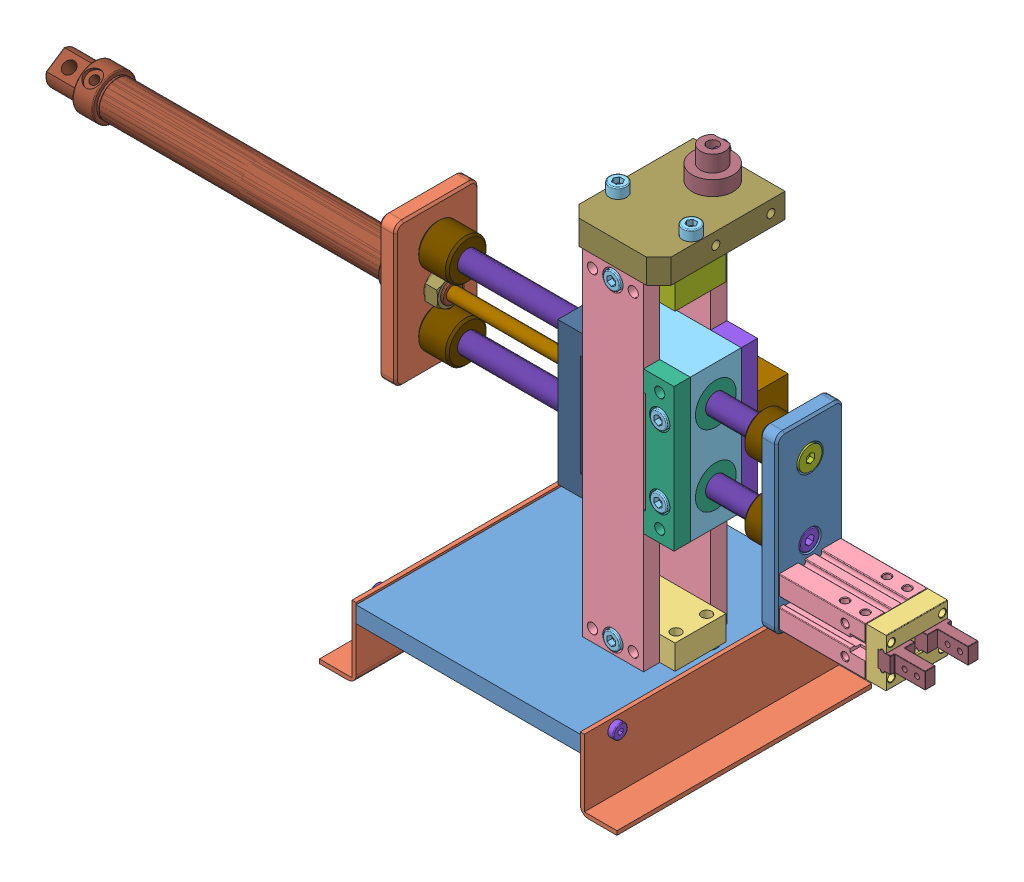
SolidWorks assembly S5, configuration Default. Lengths in mm.
Overall size (436.7 226.2 125).
64 component instances, 31 part files, 157 mates.
Components (placement in the parent):
- tam de lon-1: tam de lon [Default] at (42.5889 56.6685 101.1963) size (110 8 125)
- khoi do-1: khoi do [Default] at (98.4472 49.4552 163.6963) x (0 0 -1) z (-1 0 0) size (125 35 18)
- khoi do-2: khoi do [Default] at (-13.2695 49.4552 38.6963) x (0 0 1) z (1 0 0) size (125 35 18)
- mieng dem duoi-1: mieng dem duoi [Default] at (71.5889 64.6685 101.1963) size (45 12 25)
- thanh dan huong lon x2-1: thanh dan huong lon x2 [Default] at (71.5889 147.1685 113.6963) x (1 0 0) z (0 -1 0) size (30 8 165)
- thanh dan huong lon x2-2: thanh dan huong lon x2 [Default] at (71.5889 147.1685 88.6963) x (1 0 0) z (0 1 0) size (30 8 165)
- con truot s4 -1: con truot s4  [Default] at (79.0889 123.42 101.1963) x (-1 0 0) z (0 0 -1) size (45 70 25)
- bac lot-1: bac lot [Default] at (101.5889 140.92 101.1963) x (0 1 0) z (0 0 1) size (20 12 20)
- bac lot-2: bac lot [Default] at (101.5889 175.92 101.1963) x (0 1 0) z (0 0 1) size (20 12 20)
- bac lot-3: bac lot [Default] at (56.5889 175.92 101.1963) x (0 0.381849 -0.924225) z (0 -0.924225 -0.381849) size (20 12 20)
- bac lot-4: bac lot [Default] at (56.5889 140.92 101.1963) x (0 0.381849 -0.924225) z (0 -0.924225 -0.381849) size (20 12 20)
- mieng dem tren-1: mieng dem tren [Default] at (71.5889 217.6685 101.1963) size (45 12 25)
- thanh dan huong so 2 s4-3: thanh dan huong so 2 s4 [Default] at (94.0889 158.42 88.6963) x (-1 0 0) z (0 -1 0) size (15 8 70)
- thanh ngang-5: thanh ngang [Default] at (73.0889 155.42 65.6963) x (-1 0 0) z (0 1 0) size (57 15 25)
- tam dan huong-4: tam dan huong [Default] at (44.5889 158.42 101.1963) x (0 -1 0) z (0 0 1) size (70 12 41)
- dai oc-1: dai oc [Default] at (71.5889 158.42 65.6963) x (0 1 0) z (1 0 0) size (16 14 16)
- tam de nho-4: tam de nho [Default] at (71.5889 241.6685 90.6963) x (1 0 0) z (0 0 -1) size (45 12 62)
- dau kep truc vit-2: dau kep truc vit [Default] at (71.5889 256.8685 72.6963) x (-0.045414 0 -0.998968) z (-0.998968 0 0.045414) size (20 25 20)
- vong_dem-2: vong_dem [Default] at (71.5889 229.8685 72.6963) x (0.969315 0 0.245821) z (-0.245821 0 0.969315) size (19.6 2 19.6)
- vit me M8x150mm-2: vit me M8x150mm [Default] at (71.5889 171.8685 72.6963) x (0.826851 0 0.562421) z (0 1 0) size (10.85 10.06 150.11)
- hex nut gradec_din-2: hex nut gradec_din [Hexagon Nut ISO 4034 - M8 - N] at (71.5889 221.9685 72.6963) x (-0.899635 0 -0.436642) z (0 -1 0) size (13 15.01 7.9)
- chot dan huong-1: chot dan huong [Default] at (139.8249 175.92 101.1963) x (0 0.988897 -0.148604) z (0 0.148604 0.988897) size (10 175 10)
- chot dan huong-2: chot dan huong [Default] at (139.8249 140.92 101.1963) x (0 0.324021 0.94605) z (0 -0.94605 0.324021) size (10 175 10)
- bac chan-1: bac chan [Default] at (139.8249 175.92 101.1963) x (0 0.942027 0.335537) z (0 -0.335537 0.942027) size (20 15 20)
- bac chan-2: bac chan [Default] at (139.8249 140.92 101.1963) x (0 1 0) z (0 0 1) size (20 15 20)
- bac chan-3: bac chan [Default] at (-20.1751 175.92 101.1963) x (0 0.635792 -0.77186) z (0 0.77186 0.635792) size (20 15 20)
- bac chan-4: bac chan [Default] at (-20.1751 140.92 101.1963) x (0 0.99939 -0.03491) z (0 0.03491 0.99939) size (20 15 20)
- ban canh truoc-1: ban canh truoc [Default] at (139.8249 150.42 101.1963) x (0 0 -1) z (0 -1 0) size (33 8 86)
- ban canh sau-1: ban canh sau [Default] at (-35.1751 158.42 101.1963) x (0 0 -1) z (0 1 0) size (41 8 70)
- NMHZ2-16D-2: NMHZ2-16D [Default] at (132.8369 119.8622 123.6032) x (0 0 -1) z (1 0 0) size (30.6 23.6 52.5)
  - NMHZ2-16D Slipway-1: NMHZ2-16D Slipway [Default] at (22.4069 2.6078 57.488) size (30.1 23.6 10)
  - NMHZ2-16D cylinder-2: NMHZ2-16D cylinder [Default] at (22.4069 2.6078 14.988) size (30.6 23.6 42.5)
- socket head cap screw_din-2: socket head cap screw_din [DIN 912 M5 x 16 --- 16N] at (94.5889 175.92 79.8963) x (0 0 1) z (-1 0 0) size (21 8.5 8.5)
- socket head cap screw_din-3: socket head cap screw_din [DIN 912 M5 x 16 --- 16N] at (50.0889 151.92 66.3963) x (0 0 1) z (-1 0 0) size (21 8.5 8.5)
- socket head cap screw_din-4: socket head cap screw_din [DIN 912 M5 x 16 --- 16N] at (94.5889 164.92 66.3963) x (0 0 1) z (-1 0 0) size (21 8.5 8.5)
- socket head cap screw_din-5: socket head cap screw_din [DIN 912 M5 x 16 --- 16N] at (94.5889 140.92 79.8963) x (0 0 1) z (-1 0 0) size (21 8.5 8.5)
- socket head cap screw_din-6: socket head cap screw_din [DIN 912 M5 x 16 --- 16N] at (71.5889 70.6685 79.8963) x (0 0 1) z (-1 0 0) size (21 8.5 8.5)
- socket head cap screw_din-9: socket head cap screw_din [DIN 912 M5 x 8 --- 8N] at (71.5889 70.6685 122.4963) x (0 0 -1) z (1 0 0) size (13 8.5 8.5)
- socket head cap screw_din-10: socket head cap screw_din [DIN 912 M5 x 8 --- 8N] at (45.2889 129.42 108.6963) size (13 8.5 8.5)
- socket head cap screw_din-11: socket head cap screw_din [DIN 912 M5 x 8 --- 8N] at (45.2889 187.42 93.6963) size (13 8.5 8.5)
- thanh dan huong s4-1: thanh dan huong s4 [Default] at (94.0889 158.42 113.6963) x (-1 0 0) z (0 1 0) size (15 8 70)
- socket head cap screw_din-13: socket head cap screw_din [DIN 912 M5 x 12 --- 12N] at (94.5889 140.92 122.4963) x (0 0 -1) z (1 0 0) size (17 8.5 8.5)
- socket head cap screw_din-14: socket head cap screw_din [DIN 912 M5 x 12 --- 12N] at (94.5889 175.92 122.4963) x (0 0 -1) z (1 0 0) size (17 8.5 8.5)
- socket head cap screw_din-15: socket head cap screw_din [DIN 912 M5 x 12 --- 12N] at (53.5889 246.6685 101.1963) x (0 -1 0) z (0 0 1) size (17 8.5 8.5)
- socket head cap screw_din-16: socket head cap screw_din [DIN 912 M5 x 12 --- 12N] at (89.5889 246.6685 101.1963) x (0 -1 0) z (0 0 1) size (17 8.5 8.5)
- socket head cap screw_din-17: socket head cap screw_din [DIN 912 M5 x 12 --- 12N] at (71.5889 223.6685 79.8963) x (0 0 1) z (-1 0 0) size (17 8.5 8.5)
- socket head cap screw_din-18: socket head cap screw_din [DIN 912 M5 x 12 --- 12N] at (71.5889 223.6685 122.4963) x (0 0 -1) z (1 0 0) size (17 8.5 8.5)
- socket csink head cap screw 10642_din-2: socket csink head cap screw 10642_din [EN ISO 10642 - M6 x 8 - 8N] at (-43.3951 175.92 101.1963) x (1 0 0) z (0 0.02259 0.999745) size (8 11.34 11.34)
- socket csink head cap screw 10642_din-3: socket csink head cap screw 10642_din [EN ISO 10642 - M6 x 8 - 8N] at (148.0449 175.92 101.1963) x (-1 0 0) z (0 -0.022602 -0.999745) size (8 11.34 11.34)
- socket head thin cap screw_din-2: socket head thin cap screw_din [DIN 7984 - M6 x 10 --- 7N] at (147.6249 140.92 101.1963) x (-1 0 0) z (0 0.924225 0.381849) size (14 10 10)
- socket head thin cap screw_din-4: socket head thin cap screw_din [DIN 7984 - M6 x 10 --- 7N] at (-42.9751 140.92 101.1963) size (14 10 10)
- socket head thin cap screw_din-5: socket head thin cap screw_din [DIN 7984 - M4 x 6 --- 3.9N] at (-17.2111 60.6685 53.6963) size (8.8 7 7)
- socket head thin cap screw_din-6: socket head thin cap screw_din [DIN 7984 - M4 x 6 --- 3.9N] at (-17.2111 60.6685 148.6963) size (8.8 7 7)
- socket head thin cap screw_din-7: socket head thin cap screw_din [DIN 7984 - M4 x 6 --- 3.9N] at (102.3889 60.6685 53.6963) x (-1 0 0) z (0 0.924225 0.381849) size (8.8 7 7)
- socket head thin cap screw_din-8: socket head thin cap screw_din [DIN 7984 - M4 x 6 --- 3.9N] at (102.3889 60.6685 148.6963) x (-1 0 0) z (0 0.924225 0.381849) size (8.8 7 7)
- socket head thin cap screw_din-10: socket head thin cap screw_din [DIN 7984 - M4 x 12 --- 9.9N] at (141.4249 115.12 112.1963) size (14.8 7 7)
- socket head thin cap screw_din-11: socket head thin cap screw_din [DIN 7984 - M4 x 12 --- 9.9N] at (141.4249 130.12 90.1963) size (14.8 7 7)
- socket head thin cap screw_din-18: socket head thin cap screw_din [DIN 7984 - M3 x 5 --- 3.5N] at (71.2937 252.8685 66.203) x (0.045414 0 0.998968) z (0.400979 0.915906 -0.018229) size (7 5.5 5.5)
- Rod-1: Rod [Default] at (-92.4392 158.42 101.1963) x (0 0.871767 -0.48992) z (0 -0.48992 -0.871767) size (6.2 165 6.2)
- Nut 5-1: Nut 5 [Default] at (55.0889 158.42 101.1963) x (0 0.12782 0.991797) z (0 0.991797 -0.12782) size (11.32 3 9.8)
- 16 X 100 Cylinder bore-2: 16 X 100 Cylinder bore [Default] at (-123.3751 158.42 101.1963) x (0 0.833113 0.553102) z (-1 0 0) size (21.5 21.5 192)
- hex nut style 1 fine gradeab_din-2: hex nut style 1 fine gradeab_din [Hexagon Nut ISO 8673 - M8 x 1 - W - N] at (-28.3751 158.42 101.1963) x (0 0 -1) z (1 0 0) size (13 15.01 6.8)
- NMHZ2-16D air claw-1: NMHZ2-16D air claw [Default] at (198.3249 122.47 98.1463) x (0 0 -1) z (1 0 0) size (12 10 21)
- NMHZ2-16D air claw-2: NMHZ2-16D air claw [Default] at (198.3249 122.47 104.2463) x (0 0 1) z (1 0 0) size (12 10 21)
Mates (geometry in assembly coordinates):
- Parallel1: parallel anti-aligned: plane of tam de lon-1 through (42.5889 64.6685 101.1963) normal (0 1 0); plane of khoi do-1 through (97.5889 30.6685 38.6963) normal (0 -1 0)
- Parallel2: parallel anti-aligned: plane of tam de lon-1 through (97.5889 64.6685 38.6963) normal (1 0 0); plane of khoi do-1 through (97.5889 30.6685 38.6963) normal (-1 0 0)
- Concentric1: concentric aligned: cylinder of tam de lon-1 through (82.5889 60.6685 53.6963) axis (1 0 0) radius 2.5; cylinder of khoi do-1 through (-25.4111 60.6685 53.6963) axis (1 0 0) radius 2.5
- Coincident1: coincident anti-aligned: plane of tam de lon-1 through (97.5889 64.6685 38.6963) normal (1 0 0); plane of khoi do-1 through (97.5889 30.6685 38.6963) normal (-1 0 0)
- Parallel3: parallel anti-aligned: plane of tam de lon-1 through (42.5889 64.6685 101.1963) normal (0 1 0); plane of khoi do-2 through (-12.4111 30.6685 163.6963) normal (0 -1 0)
- Parallel4: parallel anti-aligned: plane of tam de lon-1 through (-12.4111 64.6685 38.6963) normal (-1 0 0); plane of khoi do-2 through (-12.4111 30.6685 163.6963) normal (1 0 0)
- Concentric2: concentric aligned: cylinder of tam de lon-1 through (2.5889 60.6685 148.6963) axis (-1 0 0) radius 2.5; cylinder of khoi do-2 through (110.5889 60.6685 148.6963) axis (-1 0 0) radius 2.5
- Coincident2: coincident anti-aligned: plane of tam de lon-1 through (-12.4111 64.6685 38.6963) normal (-1 0 0); plane of khoi do-2 through (-12.4111 30.6685 163.6963) normal (1 0 0)
- Concentric3: concentric aligned: cylinder of tam de lon-1 through (89.5889 56.6685 93.6963) axis (0 1 0) radius 2.75; cylinder of mieng dem duoi-1 through (89.5889 64.6685 93.6963) axis (0 1 0) radius 2.5
- Concentric4: concentric aligned: cylinder of tam de lon-1 through (53.5889 56.6685 108.6963) axis (0 1 0) radius 2.75; cylinder of mieng dem duoi-1 through (53.5889 64.6685 108.6963) axis (0 1 0) radius 2.5
- Coincident3: coincident anti-aligned: plane of tam de lon-1 through (42.5889 64.6685 101.1963) normal (0 1 0); plane of mieng dem duoi-1 through (71.5889 64.6685 101.1963) normal (0 -1 0)
- Parallel6: parallel anti-aligned: plane of mieng dem duoi-1 through (71.5889 76.6685 101.1963) normal (0 1 0); plane of thanh dan huong lon x2-1 through (56.5889 64.6685 121.6963) normal (0 -1 0)
- Parallel7: parallel anti-aligned: plane of mieng dem duoi-1 through (49.0889 76.6685 113.6963) normal (0 0 1); plane of thanh dan huong lon x2-1 through (71.5889 147.1685 113.6963) normal (0 0 -1)
- Concentric5: concentric anti-aligned: cylinder of mieng dem duoi-1 through (81.5889 70.6685 160.6963) axis (0 0 -1) radius 2.5; cylinder of thanh dan huong lon x2-1 through (81.5889 70.6685 80.4963) axis (0 0 1) radius 2.5
- Coincident4: coincident anti-aligned: plane of mieng dem duoi-1 through (49.0889 76.6685 113.6963) normal (0 0 1); plane of thanh dan huong lon x2-1 through (71.5889 147.1685 113.6963) normal (0 0 -1)
- Parallel8: parallel anti-aligned: plane of mieng dem duoi-1 through (71.5889 76.6685 101.1963) normal (0 1 0); plane of thanh dan huong lon x2-2 through (56.5889 64.6685 80.6963) normal (0 -1 0)
- Parallel9: parallel anti-aligned: plane of mieng dem duoi-1 through (49.0889 76.6685 88.6963) normal (0 0 -1); plane of thanh dan huong lon x2-2 through (71.5889 147.1685 88.6963) normal (0 0 1)
- Concentric6: concentric aligned: cylinder of mieng dem duoi-1 through (81.5889 70.6685 160.6963) axis (0 0 -1) radius 2.5; cylinder of thanh dan huong lon x2-2 through (81.5889 70.6685 121.8963) axis (0 0 -1) radius 2.5
- Coincident5: coincident anti-aligned: plane of mieng dem duoi-1 through (49.0889 76.6685 88.6963) normal (0 0 -1); plane of thanh dan huong lon x2-2 through (71.5889 147.1685 88.6963) normal (0 0 1)
- Parallel10: parallel anti-aligned: plane of mieng dem duoi-1 through (94.0889 76.6685 88.6963) normal (1 0 0); plane of con truot s4 -1 through (56.5889 193.42 113.6963) normal (-1 0 0)
- Parallel11: parallel aligned: plane of mieng dem duoi-1 through (71.5889 76.6685 101.1963) normal (0 1 0); plane of con truot s4 -1 through (79.0889 193.42 101.1963) normal (0 1 0)
- Coincident6: coincident anti-aligned: plane of thanh dan huong lon x2-2 through (71.5889 147.1685 88.6963) normal (0 0 1); plane of con truot s4 -1 through (101.5889 193.42 88.6963) normal (0 0 -1)
- Concentric7: concentric anti-aligned: cylinder of con truot s4 -1 through (126.5889 140.92 101.1963) axis (-1 0 0) radius 6; cylinder of bac lot-1 through (89.5889 140.92 101.1963) axis (1 0 0) radius 6
- Coincident14: coincident anti-aligned: plane of con truot s4 -1 through (99.5889 140.92 101.1963) normal (1 0 0); plane of bac lot-1 through (99.5889 140.92 101.1963) normal (-1 0 0)
- Concentric8: concentric anti-aligned: cylinder of con truot s4 -1 through (126.5889 175.92 101.1963) axis (-1 0 0) radius 6; cylinder of bac lot-2 through (89.5889 175.92 101.1963) axis (1 0 0) radius 6
- Coincident15: coincident anti-aligned: plane of con truot s4 -1 through (99.5889 175.92 101.1963) normal (1 0 0); plane of bac lot-2 through (99.5889 175.92 101.1963) normal (-1 0 0)
- Concentric9: concentric aligned: cylinder of con truot s4 -1 through (126.5889 175.92 101.1963) axis (-1 0 0) radius 6; cylinder of bac lot-3 through (68.5889 175.92 101.1963) axis (-1 0 0) radius 6
- Coincident16: coincident anti-aligned: plane of con truot s4 -1 through (58.5889 175.92 101.1963) normal (-1 0 0); plane of bac lot-3 through (58.5889 175.92 101.1963) normal (1 0 0)
- Concentric10: concentric aligned: cylinder of con truot s4 -1 through (126.5889 140.92 101.1963) axis (-1 0 0) radius 6; cylinder of bac lot-4 through (68.5889 140.92 101.1963) axis (-1 0 0) radius 6
- Coincident18: coincident anti-aligned: plane of con truot s4 -1 through (58.5889 140.92 101.1963) normal (-1 0 0); plane of bac lot-4 through (58.5889 140.92 101.1963) normal (1 0 0)
- Parallel23: parallel aligned: plane of thanh dan huong lon x2-2 through (56.5889 229.6685 80.6963) normal (0 1 0); plane of mieng dem tren-1 through (71.5889 229.6685 101.1963) normal (0 1 0)
- Concentric12: concentric aligned: cylinder of thanh dan huong lon x2-2 through (61.5889 223.6685 121.8963) axis (0 0 -1) radius 2.5; cylinder of mieng dem tren-1 through (61.5889 223.6685 160.6963) axis (0 0 -1) radius 2.5
- Coincident21: coincident anti-aligned: plane of thanh dan huong lon x2-2 through (71.5889 147.1685 88.6963) normal (0 0 1); plane of mieng dem tren-1 through (49.0889 229.6685 88.6963) normal (0 0 -1)
- Parallel38: parallel aligned: plane of con truot s4 -1 through (79.0889 193.42 101.1963) normal (0 1 0); plane of thanh dan huong so 2 s4-3 through (101.5889 193.42 80.6963) normal (0 1 0)
- Parallel39: parallel anti-aligned: plane of con truot s4 -1 through (101.5889 193.42 88.6963) normal (0 0 -1); plane of thanh dan huong so 2 s4-3 through (94.0889 158.42 88.6963) normal (0 0 1)
- Coincident32: coincident aligned: plane of con truot s4 -1 through (79.0889 193.42 101.1963) normal (0 1 0); plane of thanh dan huong so 2 s4-3 through (101.5889 193.42 80.6963) normal (0 1 0)
- Coincident33: coincident aligned: plane of con truot s4 -1 through (101.5889 193.42 113.6963) normal (1 0 0); plane of thanh dan huong so 2 s4-3 through (101.5889 193.42 80.6963) normal (1 0 0)
- Coincident34: coincident anti-aligned: plane of con truot s4 -1 through (101.5889 193.42 88.6963) normal (0 0 -1); plane of thanh dan huong so 2 s4-3 through (94.0889 158.42 88.6963) normal (0 0 1)
- Coincident36: coincident anti-aligned: plane of thanh dan huong lon x2-2 through (86.5889 64.6685 80.6963) normal (1 0 0); plane of thanh dan huong so 2 s4-3 through (86.5889 193.42 80.6963) normal (-1 0 0)
- Parallel42: parallel anti-aligned: plane of thanh dan huong so 2 s4-3 through (101.5889 193.42 80.6963) normal (0 1 0); plane of thanh ngang-5 through (101.5889 145.92 80.6963) normal (0 -1 0)
- Concentric26: concentric aligned: cylinder of thanh dan huong so 2 s4-3 through (94.5889 164.92 152.8963) axis (0 0 -1) radius 2.5; cylinder of thanh ngang-5 through (94.5889 164.92 124.3963) axis (0 0 -1) radius 2.75
- Parallel46: parallel aligned: plane of con truot s4 -1 through (79.0889 193.42 101.1963) normal (0 1 0); plane of tam dan huong-4 through (56.5889 193.42 80.6963) normal (0 1 0)
- Parallel47: parallel anti-aligned: plane of con truot s4 -1 through (56.5889 193.42 113.6963) normal (-1 0 0); plane of tam dan huong-4 through (55.5889 183.42 33.6963) normal (1 0 0)
- Coincident40: coincident anti-aligned: plane of con truot s4 -1 through (56.5889 193.42 113.6963) normal (-1 0 0); plane of tam dan huong-4 through (56.5889 158.42 101.1963) normal (1 0 0)
- Concentric29: concentric aligned: cylinder of con truot s4 -1 through (71.5889 187.42 93.6963) axis (-1 0 0) radius 2.5; cylinder of tam dan huong-4 through (132.5889 187.42 93.6963) axis (-1 0 0) radius 2.75
- Coincident41: coincident anti-aligned: plane of thanh dan huong so 2 s4-3 through (94.0889 158.42 80.6963) normal (0 0 -1); plane of thanh ngang-5 through (73.0889 155.42 80.6963) normal (0 0 1)
- Parallel48: parallel anti-aligned: plane of thanh ngang-5 through (73.0889 155.42 65.6963) normal (0 0 -1); plane of dai oc-1 through (80.1238 179.42 79.6963) normal (0 0 1)
- Concentric30: concentric anti-aligned: cylinder of thanh ngang-5 through (71.5889 -0.08 72.6963) axis (0 1 0) radius 5; cylinder of dai oc-1 through (71.5889 179.42 72.6963) axis (0 -1 0) radius 4
- Concentric31: concentric aligned: cylinder of thanh ngang-5 through (71.5889 158.42 236.6963) axis (0 0 -1) radius 8; cylinder of dai oc-1 through (71.5889 158.42 79.6963) axis (0 0 -1) radius 8
- Parallel53: parallel anti-aligned: plane of mieng dem tren-1 through (71.5889 229.6685 101.1963) normal (0 1 0); plane of tam de nho-4 through (71.5889 229.6685 90.6963) normal (0 -1 0)
- Parallel54: parallel anti-aligned: plane of mieng dem tren-1 through (94.0889 229.6685 88.6963) normal (1 0 0); plane of tam de nho-4 through (49.0889 229.6685 121.6963) normal (-1 0 0)
- Concentric32: concentric anti-aligned: cylinder of mieng dem tren-1 through (53.5889 157.6685 101.1963) axis (0 1 0) radius 2.5; cylinder of tam de nho-4 through (53.5889 241.6685 101.1963) axis (0 -1 0) radius 2.75
- Coincident45: coincident anti-aligned: plane of mieng dem tren-1 through (71.5889 229.6685 101.1963) normal (0 1 0); plane of tam de nho-4 through (71.5889 229.6685 90.6963) normal (0 -1 0)
- Parallel55: parallel anti-aligned: plane of tam de nho-4 through (71.5889 241.6685 90.6963) normal (0 1 0); plane of dau kep truc vit-2 through (71.5889 231.8685 72.6963) normal (0 -1 0)
- Concentric33: concentric aligned: cylinder of tam de nho-4 through (71.5889 241.6685 72.6963) axis (0 -1 0) radius 7; cylinder of dau kep truc vit-2 through (71.5889 241.6685 72.6963) axis (0 -1 0) radius 7
- Coincident46: coincident anti-aligned: plane of tam de nho-4 through (71.5889 241.6685 90.6963) normal (0 1 0); plane of dau kep truc vit-2 through (71.5889 241.6685 72.6963) normal (0 -1 0)
- Concentric34: concentric aligned: cylinder of dau kep truc vit-2 through (71.5889 246.8685 72.6963) axis (0 -1 0) radius 4; cylinder of vong_dem-2 through (71.5889 231.8685 72.6963) axis (0 -1 0) radius 4.25
- Coincident47: coincident anti-aligned: plane of dau kep truc vit-2 through (71.5889 231.8685 72.6963) normal (0 -1 0); plane of vong_dem-2 through (71.5889 231.8685 72.6963) normal (0 1 0)
- Concentric35: concentric anti-aligned: cylinder of dau kep truc vit-2 through (71.5889 246.8685 72.6963) axis (0 -1 0) radius 4; cylinder of vit me M8x150mm-2 through (71.5889 171.8685 72.6963) axis (0 1 0) radius 3.933
- Coincident48: coincident anti-aligned: plane of dau kep truc vit-2 through (71.5889 246.8685 72.6963) normal (0 -1 0); plane of vit me M8x150mm-2 through (71.5889 246.8685 72.6963) normal (0 1 0)
- Concentric37: concentric anti-aligned: cylinder of vit me M8x150mm-2 through (71.5889 171.8685 72.6963) axis (0 1 0) radius 3.933; cylinder of hex nut gradec_din-2 through (71.5889 229.8685 72.6963) axis (0 -1 0) radius 3.4
- Coincident49: coincident anti-aligned: plane of vong_dem-2 through (71.5889 229.8685 72.6963) normal (0 -1 0); plane of hex nut gradec_din-2 through (74.8661 229.8685 65.944) normal (0 1 0)
- Lock1: lock: unknown of vit me M8x150mm-2; unknown of hex nut gradec_din-2
- Lock2: lock: unknown of dau kep truc vit-2; unknown of hex nut gradec_din-2
- Concentric41: concentric anti-aligned: cylinder of bac lot-2 through (116.5889 175.92 101.1963) axis (-1 0 0) radius 5; cylinder of chot dan huong-1 through (-133.1751 175.92 101.1963) axis (1 0 0) radius 5
- Concentric42: concentric anti-aligned: cylinder of bac lot-1 through (116.5889 140.92 101.1963) axis (-1 0 0) radius 5; cylinder of chot dan huong-2 through (-133.1751 140.92 101.1963) axis (1 0 0) radius 5
- Concentric43: concentric anti-aligned: cylinder of chot dan huong-1 through (-133.1751 175.92 101.1963) axis (1 0 0) radius 5; cylinder of bac chan-1 through (139.8249 175.92 101.1963) axis (-1 0 0) radius 5
- Coincident53: coincident aligned: plane of chot dan huong-1 through (139.8249 175.92 101.1963) normal (1 0 0); plane of bac chan-1 through (139.8249 175.92 101.1963) normal (1 0 0)
- Concentric44: concentric anti-aligned: cylinder of chot dan huong-2 through (-133.1751 140.92 101.1963) axis (1 0 0) radius 5; cylinder of bac chan-2 through (139.8249 140.92 101.1963) axis (-1 0 0) radius 5
- Coincident54: coincident aligned: plane of chot dan huong-2 through (139.8249 140.92 101.1963) normal (1 0 0); plane of bac chan-2 through (139.8249 140.92 101.1963) normal (1 0 0)
- Concentric45: concentric anti-aligned: cylinder of chot dan huong-1 through (-133.1751 175.92 101.1963) axis (1 0 0) radius 5; cylinder of bac chan-3 through (-20.1751 175.92 101.1963) axis (-1 0 0) radius 5
- Coincident55: coincident aligned: plane of chot dan huong-1 through (-35.1751 175.92 101.1963) normal (-1 0 0); plane of bac chan-3 through (-35.1751 175.92 101.1963) normal (-1 0 0)
- Coincident57: coincident aligned: plane of chot dan huong-2 through (-35.1751 140.92 101.1963) normal (-1 0 0); plane of bac chan-4 through (-35.1751 140.92 101.1963) normal (-1 0 0)
- Concentric47: concentric aligned: cylinder of chot dan huong-1 through (119.8249 175.92 101.1963) axis (1 0 0) radius 3; cylinder of ban canh truoc-1 through (139.8249 175.92 101.1963) axis (1 0 0) radius 3.3
- Concentric48: concentric aligned: cylinder of chot dan huong-2 through (119.8249 140.92 101.1963) axis (1 0 0) radius 3; cylinder of ban canh truoc-1 through (139.8249 140.92 101.1963) axis (1 0 0) radius 3.3
- Coincident58: coincident anti-aligned: plane of chot dan huong-1 through (139.8249 175.92 101.1963) normal (1 0 0); plane of ban canh truoc-1 through (139.8249 150.42 101.1963) normal (-1 0 0)
- Coincident59: coincident anti-aligned: plane of chot dan huong-2 through (139.8249 140.92 101.1963) normal (1 0 0); plane of ban canh truoc-1 through (139.8249 150.42 101.1963) normal (-1 0 0)
- Concentric49: concentric aligned: cylinder of chot dan huong-1 through (-15.1751 175.92 101.1963) axis (-1 0 0) radius 3; cylinder of ban canh sau-1 through (-35.1751 175.92 101.1963) axis (-1 0 0) radius 3.3
- Concentric50: concentric aligned: cylinder of chot dan huong-2 through (-15.1751 140.92 101.1963) axis (-1 0 0) radius 3; cylinder of ban canh sau-1 through (-35.1751 140.92 101.1963) axis (-1 0 0) radius 3.3
- Coincident60: coincident anti-aligned: plane of chot dan huong-1 through (-35.1751 175.92 101.1963) normal (-1 0 0); plane of ban canh sau-1 through (-35.1751 158.42 101.1963) normal (1 0 0)
- Coincident61: coincident anti-aligned: plane of chot dan huong-2 through (-35.1751 140.92 101.1963) normal (-1 0 0); plane of ban canh sau-1 through (-35.1751 158.42 101.1963) normal (1 0 0)
- Concentric55: concentric anti-aligned: cylinder of ban canh truoc-1 through (139.8249 115.12 112.1963) axis (1 0 0) radius 2.25; cylinder of NMHZ2-16D-2/NMHZ2-16D cylinder-2 through (162.8249 115.12 112.1963) axis (-1 0 0) radius 2
- Concentric56: concentric anti-aligned: cylinder of ban canh truoc-1 through (139.8249 130.12 90.1963) axis (1 0 0) radius 2.25; cylinder of NMHZ2-16D-2/NMHZ2-16D cylinder-2 through (162.8249 130.12 90.1963) axis (-1 0 0) radius 2
- Coincident62: coincident anti-aligned: plane of ban canh truoc-1 through (147.8249 150.42 101.1963) normal (1 0 0); plane of NMHZ2-16D-2/NMHZ2-16D cylinder-2 through (147.8249 122.47 101.1963) normal (-1 0 0)
- Concentric57: concentric anti-aligned: cylinder of chot dan huong-2 through (-133.1751 140.92 101.1963) axis (1 0 0) radius 5; cylinder of bac chan-4 through (-20.1751 140.92 101.1963) axis (-1 0 0) radius 5
- Concentric61: concentric aligned: cylinder of thanh dan huong so 2 s4-3 through (94.5889 175.92 88.6963) axis (0 0 -1) radius 2.75; cylinder of socket head cap screw_din-2 through (94.5889 175.92 48.1463) axis (0 0 -1) radius 4.25
- Coincident66: coincident anti-aligned: plane of thanh dan huong so 2 s4-3 through (94.5889 175.92 84.8963) normal (0 0 -1); plane of socket head cap screw_din-2 through (94.5889 180.17 84.8963) normal (0 0 1)
- Concentric62: concentric aligned: cylinder of thanh ngang-5 through (50.0889 151.92 71.3963) axis (0 0 -1) radius 5; cylinder of socket head cap screw_din-3 through (50.0889 151.92 34.6463) axis (0 0 -1) radius 4.25
- Coincident67: coincident anti-aligned: plane of thanh ngang-5 through (50.0889 151.92 71.3963) normal (0 0 -1); plane of socket head cap screw_din-3 through (50.0889 156.17 71.3963) normal (0 0 1)
- Concentric63: concentric aligned: cylinder of thanh ngang-5 through (94.5889 164.92 124.3963) axis (0 0 -1) radius 2.75; cylinder of socket head cap screw_din-4 through (94.5889 164.92 34.6463) axis (0 0 -1) radius 4.25
- Coincident68: coincident anti-aligned: plane of thanh ngang-5 through (94.5889 164.92 71.3963) normal (0 0 -1); plane of socket head cap screw_din-4 through (94.5889 169.17 71.3963) normal (0 0 1)
- Concentric64: concentric aligned: cylinder of thanh dan huong so 2 s4-3 through (94.5889 140.92 88.6963) axis (0 0 -1) radius 2.75; cylinder of socket head cap screw_din-5 through (94.5889 140.92 48.1463) axis (0 0 -1) radius 4.25
- Coincident69: coincident anti-aligned: plane of thanh dan huong so 2 s4-3 through (94.5889 140.92 84.8963) normal (0 0 -1); plane of socket head cap screw_din-5 through (94.5889 145.17 84.8963) normal (0 0 1)
- Concentric651: concentric aligned: cylinder of thanh dan huong lon x2-2 through (71.5889 70.6685 88.6963) axis (0 0 -1) radius 2.75; cylinder of socket head cap screw_din-6 through (71.5889 70.6685 48.1463) axis (0 0 -1) radius 4.25
- Coincident701: coincident anti-aligned: plane of thanh dan huong lon x2-2 through (71.5889 70.6685 84.8963) normal (0 0 -1); plane of socket head cap screw_din-6 through (71.5889 74.9185 84.8963) normal (0 0 1)
- Concentric66: concentric aligned: cylinder of thanh dan huong lon x2-1 through (71.5889 70.6685 113.6963) axis (0 0 1) radius 2.75; cylinder of socket head cap screw_din-9 through (71.5889 70.6685 154.2463) axis (0 0 1) radius 4.25
- Coincident71: coincident anti-aligned: plane of thanh dan huong lon x2-1 through (71.5889 70.6685 117.4963) normal (0 0 1); plane of socket head cap screw_din-9 through (71.5889 74.9185 117.4963) normal (0 0 -1)
- Concentric67: concentric aligned: cylinder of tam dan huong-4 through (132.5889 129.42 108.6963) axis (-1 0 0) radius 2.75; cylinder of socket head cap screw_din-10 through (13.5389 129.42 108.6963) axis (-1 0 0) radius 4.25
- Coincident72: coincident anti-aligned: plane of tam dan huong-4 through (50.2889 129.42 108.6963) normal (-1 0 0); plane of socket head cap screw_din-10 through (50.2889 133.67 108.6963) normal (1 0 0)
- Concentric68: concentric aligned: cylinder of tam dan huong-4 through (132.5889 187.42 93.6963) axis (-1 0 0) radius 2.75; cylinder of socket head cap screw_din-11 through (13.5389 187.42 93.6963) axis (-1 0 0) radius 4.25
- Coincident73: coincident anti-aligned: plane of tam dan huong-4 through (50.2889 187.42 93.6963) normal (-1 0 0); plane of socket head cap screw_din-11 through (50.2889 191.67 93.6963) normal (1 0 0)
- Parallel62: parallel aligned: plane of con truot s4 -1 through (101.5889 193.42 113.6963) normal (0 0 1); plane of thanh dan huong s4-1 through (94.0889 158.42 121.6963) normal (0 0 1)
- Parallel63: parallel aligned: plane of con truot s4 -1 through (101.5889 193.42 113.6963) normal (1 0 0); plane of thanh dan huong s4-1 through (101.5889 123.42 121.6963) normal (1 0 0)
- Concentric71: concentric anti-aligned: cylinder of con truot s4 -1 through (94.5889 140.92 124.6963) axis (0 0 -1) radius 2.5; cylinder of thanh dan huong s4-1 through (94.5889 140.92 113.6963) axis (0 0 1) radius 2.75
- Coincident76: coincident anti-aligned: plane of con truot s4 -1 through (101.5889 193.42 113.6963) normal (0 0 1); plane of thanh dan huong s4-1 through (94.0889 158.42 113.6963) normal (0 0 -1)
- Concentric72: concentric aligned: cylinder of thanh dan huong s4-1 through (94.5889 140.92 113.6963) axis (0 0 1) radius 2.75; cylinder of socket head cap screw_din-13 through (94.5889 140.92 154.2463) axis (0 0 1) radius 4.25
- Coincident77: coincident anti-aligned: plane of thanh dan huong s4-1 through (94.5889 140.92 117.4963) normal (0 0 1); plane of socket head cap screw_din-13 through (94.5889 145.17 117.4963) normal (0 0 -1)
- Concentric73: concentric aligned: cylinder of thanh dan huong s4-1 through (94.5889 175.92 113.6963) axis (0 0 1) radius 2.75; cylinder of socket head cap screw_din-14 through (94.5889 175.92 154.2463) axis (0 0 1) radius 4.25
- Coincident78: coincident anti-aligned: plane of thanh dan huong s4-1 through (94.5889 175.92 117.4963) normal (0 0 1); plane of socket head cap screw_din-14 through (94.5889 180.17 117.4963) normal (0 0 -1)
- Concentric74: concentric anti-aligned: cylinder of tam de nho-4 through (53.5889 241.6685 101.1963) axis (0 -1 0) radius 2.75; cylinder of socket head cap screw_din-15 through (53.5889 278.4185 101.1963) axis (0 1 0) radius 4.25
- Coincident79: coincident anti-aligned: plane of tam de nho-4 through (71.5889 241.6685 90.6963) normal (0 1 0); plane of socket head cap screw_din-15 through (57.8389 241.6685 101.1963) normal (0 -1 0)
- Concentric75: concentric anti-aligned: cylinder of tam de nho-4 through (89.5889 241.6685 101.1963) axis (0 -1 0) radius 2.75; cylinder of socket head cap screw_din-16 through (89.5889 278.4185 101.1963) axis (0 1 0) radius 4.25
- Coincident80: coincident anti-aligned: plane of tam de nho-4 through (71.5889 241.6685 90.6963) normal (0 1 0); plane of socket head cap screw_din-16 through (93.8389 241.6685 101.1963) normal (0 -1 0)
- Concentric76: concentric aligned: cylinder of thanh dan huong lon x2-2 through (71.5889 223.6685 84.8963) axis (0 0 -1) radius 5; cylinder of socket head cap screw_din-17 through (71.5889 223.6685 48.1463) axis (0 0 -1) radius 4.25
- Coincident81: coincident anti-aligned: plane of thanh dan huong lon x2-2 through (71.5889 223.6685 84.8963) normal (0 0 -1); plane of socket head cap screw_din-17 through (71.5889 227.9185 84.8963) normal (0 0 1)
- Concentric77: concentric aligned: cylinder of thanh dan huong lon x2-1 through (71.5889 223.6685 113.6963) axis (0 0 1) radius 2.75; cylinder of socket head cap screw_din-18 through (71.5889 223.6685 154.2463) axis (0 0 1) radius 4.25
- Coincident82: coincident anti-aligned: plane of thanh dan huong lon x2-1 through (71.5889 223.6685 117.4963) normal (0 0 1); plane of socket head cap screw_din-18 through (71.5889 227.9185 117.4963) normal (0 0 -1)
- Coincident83: coincident aligned: cone of ban canh sau-1 through (-39.9751 175.92 101.1963) axis (1 0 0); cone of socket csink head cap screw 10642_din-2 through (-42.3451 175.92 101.1963) axis (1 0 0)
- Coincident84: coincident aligned: cone of ban canh truoc-1 through (144.6249 175.92 101.1963) axis (-1 0 0); cone of socket csink head cap screw 10642_din-3 through (146.9949 175.92 101.1963) axis (-1 0 0)
- Concentric78: concentric aligned: cylinder of ban canh truoc-1 through (139.8249 140.92 101.1963) axis (1 0 0) radius 3.3; cylinder of socket head thin cap screw_din-2 through (179.3749 140.92 101.1963) axis (1 0 0) radius 5
- Coincident85: coincident anti-aligned: plane of ban canh truoc-1 through (143.6249 140.92 101.1963) normal (1 0 0); plane of socket head thin cap screw_din-2 through (143.6249 139.0107 105.8174) normal (-1 0 0)
- Concentric79: concentric aligned: cylinder of ban canh sau-1 through (-35.1751 140.92 101.1963) axis (-1 0 0) radius 3.3; cylinder of socket head thin cap screw_din-4 through (-74.7251 140.92 101.1963) axis (-1 0 0) radius 5
- Coincident86: coincident anti-aligned: plane of ban canh sau-1 through (-38.9751 140.92 101.1963) normal (-1 0 0); plane of socket head thin cap screw_din-4 through (-38.9751 145.92 101.1963) normal (1 0 0)
- Concentric80: concentric aligned: cylinder of khoi do-2 through (110.5889 60.6685 53.6963) axis (-1 0 0) radius 2.5; cylinder of socket head thin cap screw_din-5 through (-48.9611 60.6685 53.6963) axis (-1 0 0) radius 3.5
- Coincident87: coincident anti-aligned: plane of khoi do-2 through (-14.4111 32.6685 163.6963) normal (-1 0 0); plane of socket head thin cap screw_din-5 through (-14.4111 64.1685 53.6963) normal (1 0 0)
- Concentric81: concentric aligned: cylinder of khoi do-2 through (110.5889 60.6685 148.6963) axis (-1 0 0) radius 2.5; cylinder of socket head thin cap screw_din-6 through (-48.9611 60.6685 148.6963) axis (-1 0 0) radius 3.5
- Coincident88: coincident anti-aligned: plane of khoi do-2 through (-14.4111 32.6685 163.6963) normal (-1 0 0); plane of socket head thin cap screw_din-6 through (-14.4111 64.1685 148.6963) normal (1 0 0)
- Concentric82: concentric aligned: cylinder of khoi do-1 through (-25.4111 60.6685 53.6963) axis (1 0 0) radius 2.5; cylinder of socket head thin cap screw_din-7 through (134.1389 60.6685 53.6963) axis (1 0 0) radius 3.5
- Coincident89: coincident anti-aligned: plane of khoi do-1 through (99.5889 32.6685 38.6963) normal (1 0 0); plane of socket head thin cap screw_din-7 through (99.5889 59.332 56.9311) normal (-1 0 0)
- Concentric83: concentric aligned: cylinder of khoi do-1 through (-25.4111 60.6685 148.6963) axis (1 0 0) radius 2.5; cylinder of socket head thin cap screw_din-8 through (134.1389 60.6685 148.6963) axis (1 0 0) radius 3.5
- Coincident90: coincident anti-aligned: plane of khoi do-1 through (99.5889 32.6685 38.6963) normal (1 0 0); plane of socket head thin cap screw_din-8 through (99.5889 59.332 151.9311) normal (-1 0 0)
- Concentric84: concentric anti-aligned: cylinder of ban canh truoc-1 through (139.8249 115.12 112.1963) axis (1 0 0) radius 2.25; cylinder of socket head thin cap screw_din-10 through (109.6749 115.12 112.1963) axis (-1 0 0) radius 3.5
- Coincident91: coincident anti-aligned: plane of ban canh truoc-1 through (144.2249 115.12 112.1963) normal (-1 0 0); plane of socket head thin cap screw_din-10 through (144.2249 118.62 112.1963) normal (1 0 0)
- Concentric85: concentric aligned: cylinder of ban canh truoc-1 through (144.2249 130.12 90.1963) axis (-1 0 0) radius 4; cylinder of socket head thin cap screw_din-11 through (109.6749 130.12 90.1963) axis (-1 0 0) radius 3.5
- Coincident92: coincident anti-aligned: plane of ban canh truoc-1 through (144.2249 130.12 90.1963) normal (-1 0 0); plane of socket head thin cap screw_din-11 through (144.2249 133.62 90.1963) normal (1 0 0)
- Concentric90: concentric aligned: cylinder of dau kep truc vit-2 through (71.5662 252.8685 72.1968) axis (-0.045414 0 -0.998968) radius 1.5; cylinder of socket head thin cap screw_din-18 through (69.8518 252.8685 34.4858) axis (-0.045414 0 -0.998968) radius 2.75
- Coincident97: coincident anti-aligned: plane of dau kep truc vit-2 through (71.3845 240.7907 68.201) normal (-0.045414 0 -0.998968); plane of socket head thin cap screw_din-18 through (73.9007 251.7646 68.0866) normal (0.045414 0 0.998968)
- LimitDistance3: limit distance = 23.236 mm anti-aligned: plane of bac chan-1 through (124.8249 175.92 101.1963) normal (-1 0 0); plane of con truot s4 -1 through (101.5889 193.42 113.6963) normal (1 0 0)
- LimitDistance4: limit distance = 24.2485 mm anti-aligned: plane of tam dan huong-4 through (56.5889 193.42 80.6963) normal (0 1 0); plane of mieng dem tren-1 through (71.5889 217.6685 101.1963) normal (0 -1 0)
- Concentric93: concentric anti-aligned: cylinder of con truot s4 -1 through (71.5889 158.42 101.1963) axis (-1 0 0) radius 2.5; cylinder of Rod-1 through (52.5608 158.42 101.1963) axis (1 0 0) radius 2.6
- Concentric94: concentric anti-aligned: cylinder of Rod-1 through (52.5608 158.42 101.1963) axis (1 0 0) radius 2.6; cylinder of Nut 5-1 through (56.5889 158.42 101.1963) axis (-1 0 0) radius 2.75
- Lock4: lock: unknown of Rod-1; unknown of Nut 5-1
- Coincident99: coincident anti-aligned: plane of con truot s4 -1 through (56.5889 193.42 113.6963) normal (-1 0 0); plane of Nut 5-1 through (56.5889 158.42 101.1963) normal (1 0 0)
- Concentric95: concentric anti-aligned: cylinder of Rod-1 through (72.5608 158.42 101.1963) axis (-1 0 0) radius 3.1; cylinder of 16 X 100 Cylinder bore-2 through (-202.3751 158.42 101.1963) axis (1 0 0) radius 3.25
- LimitDistance9: limit distance = 100.9359 mm anti-aligned: plane of Rod-1 through (-92.4392 158.42 101.1963) normal (-1 0 0); plane of 16 X 100 Cylinder bore-2 through (-193.3751 158.42 101.1963) normal (1 0 0)
- Coincident103: coincident anti-aligned: plane of ban canh sau-1 through (-39.1751 158.42 101.1963) normal (-1 0 0); plane of 16 X 100 Cylinder bore-2 through (-39.1751 158.42 101.1963) normal (1 0 0)
- Concentric96: concentric aligned: cylinder of 16 X 100 Cylinder bore-2 through (-69.7713 158.42 101.1963) axis (1 0 0) radius 5.1; cylinder of hex nut style 1 fine gradeab_din-2 through (-53.4126 158.42 101.1963) axis (1 0 0) radius 4
- Coincident104: coincident anti-aligned: plane of ban canh sau-1 through (-35.1751 158.42 101.1963) normal (1 0 0); plane of hex nut style 1 fine gradeab_din-2 through (-35.1751 158.42 114.1963) normal (-1 0 0)
- Parallel64: parallel anti-aligned: plane of NMHZ2-16D-2/NMHZ2-16D Slipway-1 through (196.3249 122.47 123.6963) normal (1 0 0); plane of NMHZ2-16D air claw-1 through (196.3249 122.47 86.1463) normal (-1 0 0)
- Coincident105: coincident anti-aligned: plane of NMHZ2-16D-2/NMHZ2-16D Slipway-1 through (196.3249 122.47 123.6963) normal (1 0 0); plane of NMHZ2-16D air claw-1 through (196.3249 122.47 86.1463) normal (-1 0 0)
- Concentric97: concentric anti-aligned: cylinder of NMHZ2-16D-2/NMHZ2-16D Slipway-1 through (198.3249 126.47 123.6963) axis (0 0 -1) radius 1; cylinder of NMHZ2-16D air claw-1 through (198.3249 126.47 86.1463) axis (0 0 1) radius 1
- Parallel65: parallel anti-aligned: plane of NMHZ2-16D-2/NMHZ2-16D Slipway-1 through (196.3249 122.47 123.6963) normal (1 0 0); plane of NMHZ2-16D air claw-2 through (196.3249 122.47 116.2463) normal (-1 0 0)
- Parallel66: parallel anti-aligned: plane of NMHZ2-16D air claw-1 through (198.3249 126.47 86.1463) normal (0 1 0); plane of NMHZ2-16D air claw-2 through (198.3249 118.47 116.2463) normal (0 -1 0)
- Coincident106: coincident anti-aligned: plane of NMHZ2-16D-2/NMHZ2-16D Slipway-1 through (196.3249 122.47 123.6963) normal (1 0 0); plane of NMHZ2-16D air claw-2 through (196.3249 122.47 116.2463) normal (-1 0 0)
- Concentric98: concentric aligned: cylinder of NMHZ2-16D-2/NMHZ2-16D Slipway-1 through (198.3249 126.47 123.6963) axis (0 0 -1) radius 1; cylinder of NMHZ2-16D air claw-2 through (198.3249 126.47 116.2463) axis (0 0 -1) radius 1
- Coincident107: coincident aligned: plane of NMHZ2-16D-2/NMHZ2-16D Slipway-1 through (200.3249 139.9612 86.1463) normal (0 0 -1); plane of NMHZ2-16D air claw-1 through (198.3249 122.47 86.1463) normal (0 0 -1)
- Coincident108: coincident aligned: plane of NMHZ2-16D-2/NMHZ2-16D Slipway-1 through (200.3249 139.9612 116.2463) normal (0 0 1); plane of NMHZ2-16D air claw-2 through (198.3249 122.47 116.2463) normal (0 0 1)
